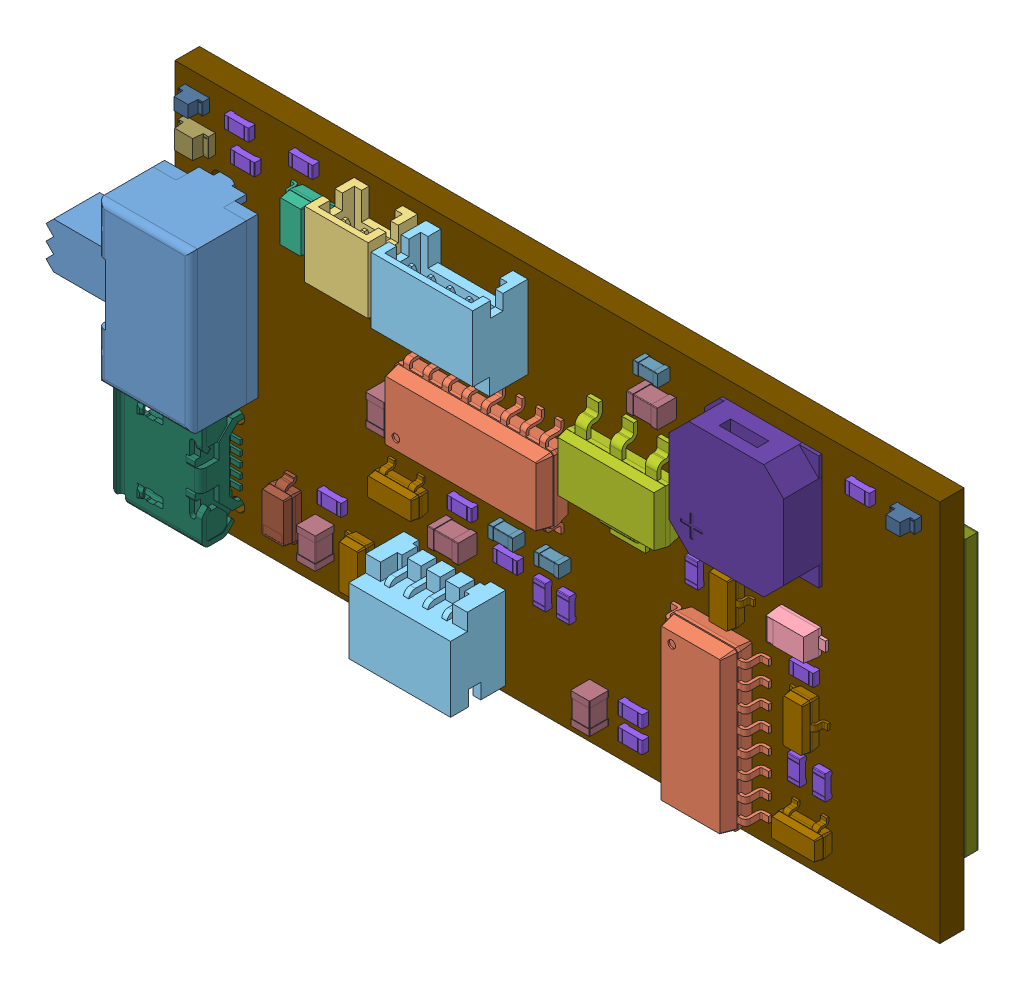
SolidWorks assembly GripMeter_PCB, configuration Predeterminado. Lengths in mm.
Overall size (53.88 25 9.73).
89 component instances, 18 part files, 0 mates.
Components (placement in the parent):
- User_Library-SK-22D02-PG4-1: User_Library-SK-22D02-PG4 [Predeterminado] at (103.17 -135.39 1.65) x (0 1 0) z (0 0 1) size (10.4 10.1 7.6)
  - COMPOUND-1: COMPOUND [Predeterminado] at origin size (10.4 10.1 7.6)
- SOP-16_4.4x10.4mm_P1.27mm-1: SOP-16_4.4x10.4mm_P1.27mm [Predeterminado] at (120.83 -135.77 1.65) x (0 1 0) z (0 0 1) size (6.4 10.4 2.1)
  - SOLID-1: SOLID [Predeterminado] at origin size (6.4 10.4 2.1)
- df13-2p-1_25ds_50_-1: df13-2p-1_25ds_50_ [Predeterminado] at (98.16 -128.54 28.65) x (0 0 1) z (-1 0 0) size (5.9 5.4 4.15)
  - COMPOUND_2-1: COMPOUND_2 [Predeterminado] at origin size (5.9 5.4 4.15)
- D_SOD-123F-1: D_SOD-123F [Predeterminado] at (141.02 -136.69 1.65) size (3.5 1.6 1.1)
  - SOLID_2-1: SOLID_2 [Predeterminado] at origin size (3.5 1.6 1.1)
- df13-4p-1_25ds_50_-1: df13-4p-1_25ds_50_ [Predeterminado] at (132.8 -146.68 29.15) x (0 0 1) z (1 0 0) size (5.9 5.4 6.65)
  - COMPOUND_3-1: COMPOUND_3 [Predeterminado] at origin size (5.9 5.4 6.65)
- df13-4p-1_25ds_50_-2: df13-4p-1_25ds_50_ [Predeterminado] at (105.5 -128.48 29.15) x (0 0 1) z (-1 0 0) size (5.9 5.4 6.65)
  - COMPOUND_3-1: COMPOUND_3 [Predeterminado] at origin size (5.9 5.4 6.65)
- SOP-16_4.4x10.4mm_P1.27mm-2: SOP-16_4.4x10.4mm_P1.27mm [Predeterminado] at (135.86 -143.9 1.65) size (6.4 10.4 2.1)
  - SOLID-1: SOLID [Predeterminado] at origin size (6.4 10.4 2.1)
- SOT-23-5-1: SOT-23-5 [Predeterminado] at (109.15 -129.05 1.65) x (-1 0 0) z (0 0 1) size (2.8 2.9 1.55)
  - SOLID_3-1: SOLID_3 [Predeterminado] at origin size (2.8 2.9 1.55)
- SOT-223-1: SOT-223 [Predeterminado] at (129.92 -133.71 1.65) x (0 -1 0) z (0 0 1) size (7 6.5 1.7)
  - SOLID_4-1: SOLID_4 [Predeterminado] at origin size (7 6.5 1.7)
- R_0603_1608Metric-1: R_0603_1608Metric [Predeterminado] at (104.5 -126.34 1.65) size (1.6 0.8 0.45)
  - SOLID_5-1: SOLID_5 [Predeterminado] at origin size (1.6 0.8 0.45)
- R_0603_1608Metric-2: R_0603_1608Metric [Predeterminado] at (134.25 -136.63 1.65) x (0 1 0) z (0 0 1) size (1.6 0.8 0.45)
  - SOLID_5-1: SOLID_5 [Predeterminado] at origin size (1.6 0.8 0.45)
- R_0603_1608Metric-3: R_0603_1608Metric [Predeterminado] at (122.06 -142.08 1.65) size (1.6 0.8 0.45)
  - SOLID_5-1: SOLID_5 [Predeterminado] at origin size (1.6 0.8 0.45)
- R_0603_1608Metric-4: R_0603_1608Metric [Predeterminado] at (119.075 -140.6 1.65) size (1.6 0.8 0.45)
  - SOLID_5-1: SOLID_5 [Predeterminado] at origin size (1.6 0.8 0.45)
- R_0603_1608Metric-5: R_0603_1608Metric [Predeterminado] at (125.86 -142.8 1.65) x (0 -1 0) z (0 0 1) size (1.6 0.8 0.45)
  - SOLID_5-1: SOLID_5 [Predeterminado] at origin size (1.6 0.8 0.45)
- R_0603_1608Metric-6: R_0603_1608Metric [Predeterminado] at (124.3 -142.84 1.65) x (0 -1 0) z (0 0 1) size (1.6 0.8 0.45)
  - SOLID_5-1: SOLID_5 [Predeterminado] at origin size (1.6 0.8 0.45)
- R_0603_1608Metric-7: R_0603_1608Metric [Predeterminado] at (130.25 -148.14 1.65) x (-1 0 0) z (0 0 1) size (1.6 0.8 0.45)
  - SOLID_5-1: SOLID_5 [Predeterminado] at origin size (1.6 0.8 0.45)
- R_0603_1608Metric-8: R_0603_1608Metric [Predeterminado] at (130.25 -146.68 1.65) size (1.6 0.8 0.45)
  - SOLID_5-1: SOLID_5 [Predeterminado] at origin size (1.6 0.8 0.45)
- R_0603_1608Metric-9: R_0603_1608Metric [Predeterminado] at (110.57 -144.55 1.65) x (-1 0 0) z (0 0 1) size (1.6 0.8 0.45)
  - SOLID_5-1: SOLID_5 [Predeterminado] at origin size (1.6 0.8 0.45)
- R_0603_1608Metric-10: R_0603_1608Metric [Predeterminado] at (104.9 -128.1 1.65) x (-1 0 0) z (0 0 1) size (1.6 0.8 0.45)
  - SOLID_5-1: SOLID_5 [Predeterminado] at origin size (1.6 0.8 0.45)
- R_0603_1608Metric-11: R_0603_1608Metric [Predeterminado] at (108.7 -126.35 1.65) size (1.6 0.8 0.45)
  - SOLID_5-1: SOLID_5 [Predeterminado] at origin size (1.6 0.8 0.45)
- R_0603_1608Metric-12: R_0603_1608Metric [Predeterminado] at (142.59 -144.46 1.65) x (0 -1 0) z (0 0 1) size (1.6 0.8 0.45)
  - SOLID_5-1: SOLID_5 [Predeterminado] at origin size (1.6 0.8 0.45)
- R_0603_1608Metric-13: R_0603_1608Metric [Predeterminado] at (141.425 -138.75 1.65) x (-1 0 0) z (0 0 1) size (1.6 0.8 0.45)
  - SOLID_5-1: SOLID_5 [Predeterminado] at origin size (1.6 0.8 0.45)
- R_0603_1608Metric-14: R_0603_1608Metric [Predeterminado] at (145.09 -126.72 1.65) size (1.6 0.8 0.45)
  - SOLID_5-1: SOLID_5 [Predeterminado] at origin size (1.6 0.8 0.45)
- R_0603_1608Metric-15: R_0603_1608Metric [Predeterminado] at (140.93 -144.46 1.65) x (0 -1 0) z (0 0 1) size (1.6 0.8 0.45)
  - SOLID_5-1: SOLID_5 [Predeterminado] at origin size (1.6 0.8 0.45)
- SOT-23-1: SOT-23 [Predeterminado] at (136.76 -136.63 1.65) size (2.5 3 1.2)
  - SOLID_6-1: SOLID_6 [Predeterminado] at origin size (2.5 3 1.2)
- SOT-23-2: SOT-23 [Predeterminado] at (115.26 -141.56 1.65) x (0 -1 0) z (0 0 1) size (2.5 3 1.2)
  - SOLID_6-1: SOLID_6 [Predeterminado] at origin size (2.5 3 1.2)
- SOT-23-3: SOT-23 [Predeterminado] at (112.57 -147.03 1.65) size (2.5 3 1.2)
  - SOLID_6-1: SOLID_6 [Predeterminado] at origin size (2.5 3 1.2)
- SOT-23-4: SOT-23 [Predeterminado] at (141.66 -147.65 1.65) x (0 -1 0) z (0 0 1) size (2.5 3 1.2)
  - SOLID_6-1: SOLID_6 [Predeterminado] at origin size (2.5 3 1.2)
- SOT-23-5: SOT-23 [Predeterminado] at (141.62 -141.23 1.65) size (2.5 3 1.2)
  - SOLID_6-1: SOLID_6 [Predeterminado] at origin size (2.5 3 1.2)
- LED_0603_1608Metric-1: LED_0603_1608Metric [Predeterminado] at (101.54 -126.32 1.65) x (-1 0 0) z (0 0 1) size (1.6 0.8 1.1)
  - SOLID_7-1: SOLID_7 [Predeterminado] at origin size (1.6 0.8 1.1)
- LED_0603_1608Metric-2: LED_0603_1608Metric [Predeterminado] at (148.09 -126.72 1.65) x (-1 0 0) z (0 0 1) size (1.6 0.8 1.1)
  - SOLID_7-1: SOLID_7 [Predeterminado] at origin size (1.6 0.8 1.1)
- D_SOD-123-1: D_SOD-123 [Predeterminado] at (107.7 -146.39 1.65) x (0 1 0) z (0 0 1) size (3.8 1.6 1.25)
  - SOLID_8-1: SOLID_8 [Predeterminado] at origin size (3.8 1.6 1.25)
- LED_0805_2012Metric-1: LED_0805_2012Metric [Predeterminado] at (101.72 -128.32 1.65) size (2 1.25 1.1)
  - SOLID_9-1: SOLID_9 [Predeterminado] at origin size (2 1.25 1.1)
- C_0805_2012Metric-1: C_0805_2012Metric [Predeterminado] at (114.38 -137.23 1.65) x (0 1 0) z (0 0 1) size (2 1.25 1.25)
  - SOLID_10-1: SOLID_10 [Predeterminado] at origin size (2 1.25 1.25)
- C_0603_1608Metric-1: C_0603_1608Metric [Predeterminado] at (125.13 -140.58 1.65) size (1.6 0.8 0.8)
  - SOLID_11-1: SOLID_11 [Predeterminado] at origin size (1.6 0.8 0.8)
- C_0603_1608Metric-2: C_0603_1608Metric [Predeterminado] at (122.13 -140.57 1.65) size (1.6 0.8 0.8)
  - SOLID_11-1: SOLID_11 [Predeterminado] at origin size (1.6 0.8 0.8)
- C_0805_2012Metric-2: C_0805_2012Metric [Predeterminado] at (118.81 -142.41 1.65) size (2 1.25 1.25)
  - SOLID_10-1: SOLID_10 [Predeterminado] at origin size (2 1.25 1.25)
- C_0603_1608Metric-3: C_0603_1608Metric [Predeterminado] at (131.61 -126.52 1.65) size (1.6 0.8 0.8)
  - SOLID_11-1: SOLID_11 [Predeterminado] at origin size (1.6 0.8 0.8)
- C_0805_2012Metric-3: C_0805_2012Metric [Predeterminado] at (131.83 -128.25 1.65) size (2 1.25 1.25)
  - SOLID_10-1: SOLID_10 [Predeterminado] at origin size (2 1.25 1.25)
- C_0805_2012Metric-4: C_0805_2012Metric [Predeterminado] at (109.85 -147.04 1.65) x (0 1 0) z (0 0 1) size (2 1.25 1.25)
  - SOLID_10-1: SOLID_10 [Predeterminado] at origin size (2 1.25 1.25)
- C_0805_2012Metric-5: C_0805_2012Metric [Predeterminado] at (127.78 -147.43 1.65) x (0 -1 0) z (0 0 1) size (2 1.25 1.25)
  - SOLID_10-1: SOLID_10 [Predeterminado] at origin size (2 1.25 1.25)
- Micro_USB-B_Female_5Pin_SMD-1: Micro_USB-B_Female_5Pin_SMD [Predeterminado] at (104.29 -145.58 2.9) x (0 -1 0) z (-1 0 0) size (8.05 3.73 5.8)
  - COMPOUND_4-1: COMPOUND_4 [Predeterminado] at origin size (8.05 3.73 5.8)
- User_Library-ESP321-1: User_Library-ESP321 [Predeterminado] at (137.2 -137 -0.05) x (0 1 0) z (0 0 -1) size (18 25.5 2.95)
  - COMPOUND_5-1: COMPOUND_5 [Predeterminado] at origin size (18 25.5 2.95)
- User_Library-YX7525P-1: User_Library-YX7525P [Predeterminado] at (138.6 -129.83 1.65) size (7.56 7.56 2.51)
  - SOLID_12-1: SOLID_12 [Predeterminado] at origin size (7.56 7.56 2.51)
- COMPOUND_6-1: COMPOUND_6 [Predeterminado] at origin size (50 25 1.6)
